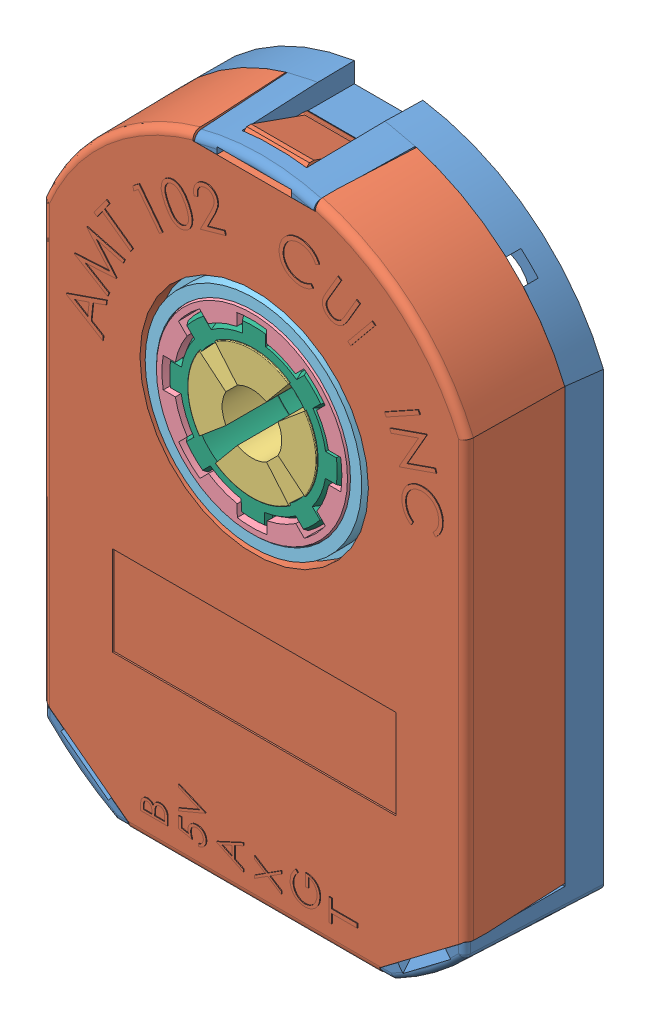
SolidWorks assembly AARL_QR_EL_EN1-CUI_DEVICES_cui_devices_amt102-0048-i4000-s, configuration Default. Lengths in mm.
Overall size (36.33 46.23 9.15).
9 component instances, 9 part files, 0 mates.
Components (placement in the parent):
- AARL_QR_EL_EN1_001-CUI_DEVICES_amt-102-base-rev-k-1: AARL_QR_EL_EN1_001-CUI_DEVICES_amt-102-base-rev-k [Default] x (-1 0 0) z (0 0 -1) size (28.83 43.41 9.03)
- AARL_QR_EL_EN1_002-CUI_DEVICES_amt-102-top-cover-rev-h-1: AARL_QR_EL_EN1_002-CUI_DEVICES_amt-102-top-cover-rev-h [Default] at (0 0 5.23) x (-1 0 0) z (0 0 -1) size (28.6 43.26 6.55)
- AARL_QR_EL_EN1_003-CUI_DEVICES_amt-sleeve-rev-d(4mm)-1: AARL_QR_EL_EN1_003-CUI_DEVICES_amt-sleeve-rev-d(4mm) [Default] at (0 0 -2.42) x (0.999996 0.002864 0) z (0 0 1) size (10.79 10.79 7.8)
- AARL_QR_EL_EN1_004-CUI_DEVICES_amt-hub-top-rev-d1-1: AARL_QR_EL_EN1_004-CUI_DEVICES_amt-hub-top-rev-d1 [Default] at (0 0 2.13) x (0.999996 0.002864 0) z (0 0 1) size (14 14 5.67)
- AARL_QR_EL_EN1_005-CUI_DEVICES_amt-hub-bottom-rev-b-1: AARL_QR_EL_EN1_005-CUI_DEVICES_amt-hub-bottom-rev-b [Default] at (0 0 2.43) x (0.999998 -0.001942 0) z (0 0 1) size (17.3 17.3 3.2)
- AARL_QR_EL_EN1_006-CUI_DEVICES_amt10x-shaft-adaptor-rev-e-1: AARL_QR_EL_EN1_006-CUI_DEVICES_amt10x-shaft-adaptor-rev-e [Default] at (0 0 0.03) x (0.999996 0.002864 0) z (0 0 1) size (11.8 11.8 7.8)
- AARL_QR_EL_EN1_007-CUI_DEVICES_receiver-board-1: AARL_QR_EL_EN1_007-CUI_DEVICES_receiver-board [Default] at (72.2834 -20.351 3.03) x (-1 0 0) z (0 0 -1) size (26.5 26.62 0.41)
- AARL_QR_EL_EN1_008-CUI_DEVICES_rotor-board-rev f-1: AARL_QR_EL_EN1_008-CUI_DEVICES_rotor-board-rev f [Default] at (0 0 2.13) x (0.807874 -0.589355 0) z (0 0 1) size (26 26 0.3)
- AARL_QR_EL_EN1_009-CUI_DEVICES_transmitter-board amt10(amt-102)-1: AARL_QR_EL_EN1_009-CUI_DEVICES_transmitter-board amt10(amt-102) [Default] at (19.1596 -17.1102 1.22) x (-1 0 0) z (0 0 -1) size (26.63 38.43 4.41)
